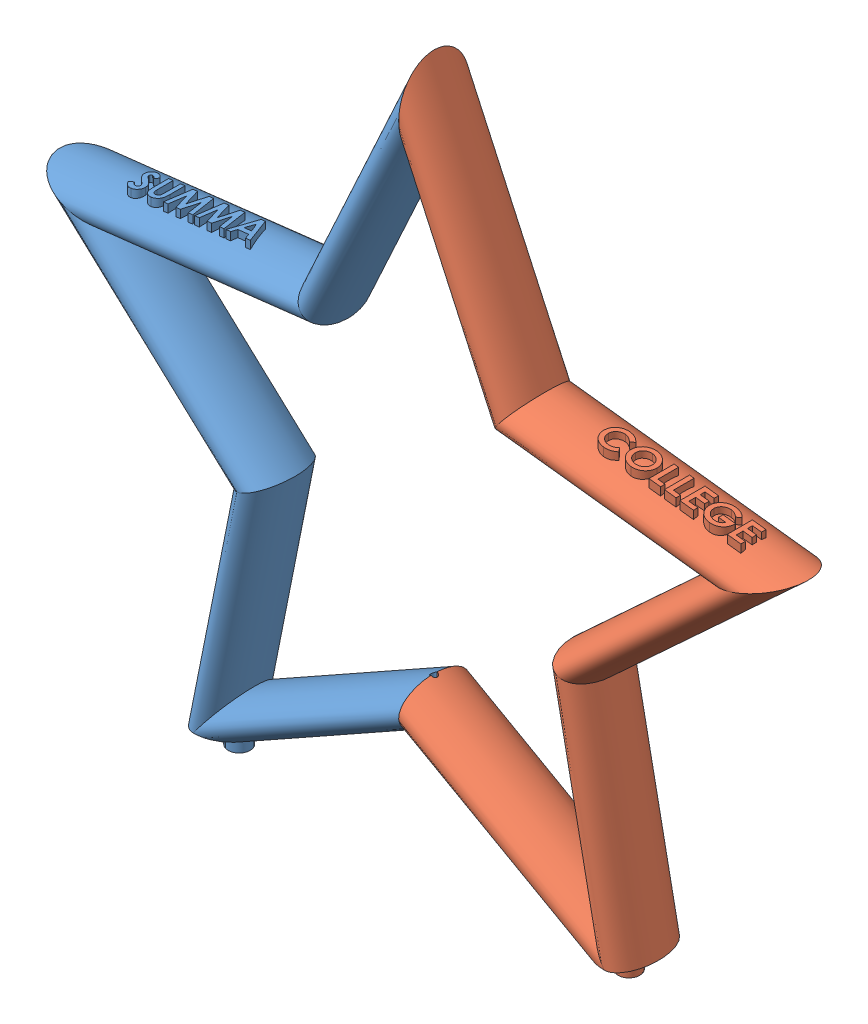
SolidWorks assembly Assem1, configuration Default. Lengths in mm.
Overall size (240.62 223.48 24.94).
2 component instances, 2 part files, 3 mates.
Components (placement in the parent):
- bovenstuk ster x1.5 met pin links paars 2-1: bovenstuk ster x1.5 met pin links paars 2 [Default] at (107.9016 39.8606 210.718) size (124.81 223.44 24.94)
- bovenstuk ster x1.5 met pin rechts geel 2-1: bovenstuk ster x1.5 met pin rechts geel 2 [Default] at (107.9016 39.9006 210.718) size (124.81 223.44 24.68)
Mates (geometry in assembly coordinates):
- Concentric1: concentric: cylinder of bovenstuk ster x1.5 met pin links paars 2-1 through (112.4016 239.8606 206.718) axis (-1 0 0) radius 2.5; cylinder of bovenstuk ster x1.5 met pin rechts geel 2-1 through (120.1914 239.8606 206.718) axis (-1 0 0) radius 2.5
- Concentric2: concentric: cylinder of bovenstuk ster x1.5 met pin links paars 2-1 through (103.4016 239.8606 214.718) axis (1 0 0) radius 2.5; cylinder of bovenstuk ster x1.5 met pin rechts geel 2-1 through (111.1914 239.8606 214.718) axis (1 0 0) radius 2.5
- Coincident1: coincident: plane of bovenstuk ster x1.5 met pin links paars 2-1 through (107.9016 39.8606 210.718) normal (1 0 0); plane of bovenstuk ster x1.5 met pin rechts geel 2-1 through (107.9016 39.9006 210.718) normal (-1 0 0)
